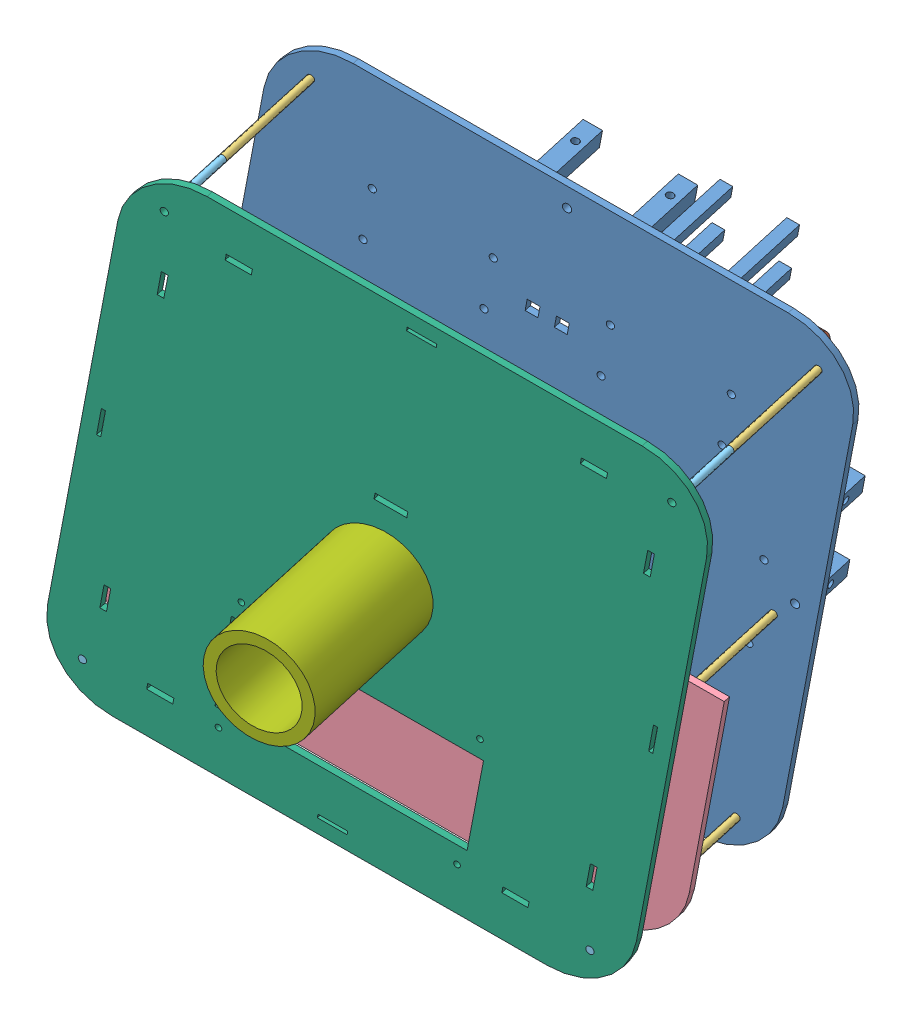
SolidWorks assembly Ensamblaje2.0, configuration Predeterminado. Lengths in mm.
Overall size (289.33 274.17 217.06).
19 component instances, 8 part files, 35 mates.
Components (placement in the parent):
- Basemenor 3.1-1: Basemenor 3.1 [Predeterminado] at (76.808 218.5631 285.9121) x (0.963383 -0.187504 -0.191664) z (0.18702 -0.042323 0.981444) size (230 230 43)
- Portamotores 3.1-1: Portamotores 3.1 [Predeterminado] at (16.9095 289.3159 299.1036) x (0.192136 0.981352 0.005706) z (0.963383 -0.187504 -0.191664) size (30 47 56.5)
- Portamotores 3.1-2: Portamotores 3.1 [Predeterminado] at (136.239 147.9161 270.2671) x (-0.192136 -0.981352 -0.005706) z (-0.963383 0.187504 0.191664) size (30 47 56.5)
- Portamotores 3.1-3: Portamotores 3.1 [Predeterminado] at (158.5268 261.7529 270.929) x (-0.192136 -0.981352 -0.005706) z (-0.963383 0.187504 0.191664) size (30 47 56.5)
- Portamotores 3.1-4: Portamotores 3.1 [Predeterminado] at (-5.3783 175.4792 298.4417) x (0.192136 0.981352 0.005706) z (0.963383 -0.187504 -0.191664) size (30 47 56.5)
- SIMULACION_Hexamonoxipuff-1: SIMULACION_Hexamonoxipuff [Predeterminado] at (191.9298 297.1399 270.4203) x (0.982348 0.003982 -0.18702) z (0.18702 -0.042323 0.981444) size (3.2 3.2 50)
- SIMULACION_Hexamonoxipuff-2: SIMULACION_Hexamonoxipuff [Predeterminado] at (153.8321 102.5533 269.2888) x (0.982348 0.003982 -0.18702) z (0.18702 -0.042323 0.981444) size (3.2 3.2 50)
- SIMULACION_Hexamonoxipuff-3: SIMULACION_Hexamonoxipuff [Predeterminado] at (0.906 334.319 308.4242) x (0.982348 0.003982 -0.18702) z (0.18702 -0.042323 0.981444) size (3.2 3.2 50)
- SIMULACION_Hexamonoxipuff-4: SIMULACION_Hexamonoxipuff [Predeterminado] at (-37.1916 139.7324 307.2927) x (0.982348 0.003982 -0.18702) z (0.18702 -0.042323 0.981444) size (3.2 3.2 50)
- SIMULACION_PCB-1: SIMULACION_PCB [Predeterminado] at (75.6722 159.8923 337.6006) x (0.963383 -0.187504 -0.191664) z (0.18702 -0.042323 0.981444) size (230 115 3)
- SIMULACION_Hexamonoxipuff-5: SIMULACION_Hexamonoxipuff [Predeterminado] at (-19.8993 228.054 307.8063) x (0.982348 0.003982 -0.18702) z (0.18702 -0.042323 0.981444) size (3.2 3.2 50)
- SIMULACION_Hexamonoxipuff-6: SIMULACION_Hexamonoxipuff [Predeterminado] at (171.1244 190.8749 269.8023) x (0.982348 0.003982 -0.18702) z (0.18702 -0.042323 0.981444) size (3.2 3.2 50)
- SIMULACION_Hexamonoxipuff_Chico-1: SIMULACION_Hexamonoxipuff_Chico [Predeterminado] at (-27.2796 137.4893 359.3092) x (0.982348 0.003982 -0.18702) z (0.18702 -0.042323 0.981444) size (3.2 3.2 30)
- SIMULACION_Hexamonoxipuff_Chico-2: SIMULACION_Hexamonoxipuff_Chico [Predeterminado] at (10.257 332.2028 357.4964) x (0.982348 0.003982 -0.18702) z (0.18702 -0.042323 0.981444) size (3.2 3.2 30)
- SIMULACION_Hexamonoxipuff_Chico-3: SIMULACION_Hexamonoxipuff_Chico [Predeterminado] at (201.2807 295.0237 319.4925) x (0.982348 0.003982 -0.18702) z (0.18702 -0.042323 0.981444) size (3.2 3.2 30)
- SIMULACION_Hexamonoxipuff_Chico-4: SIMULACION_Hexamonoxipuff_Chico [Predeterminado] at (163.7442 100.3102 321.3053) x (0.982348 0.003982 -0.18702) z (0.18702 -0.042323 0.981444) size (3.2 3.2 30)
- Basemayor-1: Basemayor [Predeterminado] at (92.3306 215.0503 367.372) x (0.963383 -0.187504 -0.191664) z (0.18702 -0.042323 0.981444) size (230 230 3)
- Cilindrokits-1: Cilindrokits [Predeterminado] at (77.3691 218.4361 288.8565) x (0.982328 0.000534 -0.187165) z (0.18702 -0.042323 0.981444) size (43.2 43.2 150)
- Portakits-1: Portakits [Predeterminado] at (50.1039 224.7974 267.8728) x (0.199566 0.978827 0.04552) z (0.973839 -0.192968 -0.120005) size (40 40 50.08)
Mates (geometry in assembly coordinates):
- Concéntrica7: concentric aligned: circle of Basemenor 3.1-1; circle of Portamotores 3.1-1
- Concéntrica8: concentric aligned: circle of Basemenor 3.1-1; circle of Portamotores 3.1-1
- Coincidente4: coincident anti-aligned: plane of Basemenor 3.1-1 through (76.808 218.5631 285.9121) normal (-0.18702 0.042323 -0.981444); plane of Portamotores 3.1-1 through (72.048 293.8581 290.0662) normal (0.18702 -0.042323 0.981444)
- Concéntrica9: concentric aligned: circle of Basemenor 3.1-1; circle of Portamotores 3.1-3
- Concéntrica10: concentric aligned: circle of Basemenor 3.1-1; circle of Portamotores 3.1-3
- Coincidente5: coincident anti-aligned: plane of Basemenor 3.1-1 through (76.808 218.5631 285.9121) normal (-0.18702 0.042323 -0.981444); plane of Portamotores 3.1-3 through (103.8558 257.1049 282.4201) normal (0.18702 -0.042323 0.981444)
- Concéntrica11: concentric aligned: circle of Basemenor 3.1-1; circle of Portamotores 3.1-2
- Concéntrica12: concentric aligned: circle of Basemenor 3.1-1; circle of Portamotores 3.1-2
- Coincidente6: coincident anti-aligned: plane of Basemenor 3.1-1 through (76.808 218.5631 285.9121) normal (-0.18702 0.042323 -0.981444); plane of Portamotores 3.1-2 through (81.568 143.2681 281.7581) normal (0.18702 -0.042323 0.981444)
- Concéntrica13: concentric aligned: circle of Basemenor 3.1-1; circle of Portamotores 3.1-4
- Concéntrica14: concentric aligned: circle of Basemenor 3.1-1; circle of Portamotores 3.1-4
- Coincidente8: coincident anti-aligned: plane of Basemenor 3.1-1 through (76.808 218.5631 285.9121) normal (-0.18702 0.042323 -0.981444); plane of Portamotores 3.1-4 through (49.7602 180.0213 289.4042) normal (0.18702 -0.042323 0.981444)
- Coincidente10: coincident aligned: circle of Basemenor 3.1-1; circle of SIMULACION_Hexamonoxipuff-1
- Coincidente11: coincident aligned: circle of Basemenor 3.1-1; circle of SIMULACION_Hexamonoxipuff-2
- Coincidente12: coincident aligned: circle of Basemenor 3.1-1; circle of SIMULACION_Hexamonoxipuff-3
- Coincidente13: coincident anti-aligned: circle of Basemenor 3.1-1; cylinder of SIMULACION_Hexamonoxipuff-4 through (-27.8406 137.6162 356.3649) axis (-0.18702 0.042323 -0.981444) radius 1.6
- Coincidente14: coincident aligned: circle of Basemenor 3.1-1; circle of SIMULACION_Hexamonoxipuff-4
- Coincidente15: coincident aligned: circle of SIMULACION_Hexamonoxipuff-4; circle of SIMULACION_PCB-1
- Coincidente17: coincident aligned: circle of SIMULACION_Hexamonoxipuff-2; circle of SIMULACION_PCB-1
- Coincidente18: coincident aligned: circle of Basemenor 3.1-1; circle of SIMULACION_Hexamonoxipuff-5
- Coincidente19: coincident anti-aligned: circle of Basemenor 3.1-1; cylinder of SIMULACION_Hexamonoxipuff-6 through (180.4754 188.7588 318.8745) axis (-0.18702 0.042323 -0.981444) radius 1.6
- Coincidente20: coincident aligned: circle of Basemenor 3.1-1; circle of SIMULACION_Hexamonoxipuff-6
- Coincidente21: coincident anti-aligned: circle of SIMULACION_PCB-1; cylinder of SIMULACION_Hexamonoxipuff_Chico-1 through (-21.669 136.2196 388.7525) axis (-0.18702 0.042323 -0.981444) radius 1.6
- Coincidente22: coincident aligned: circle of SIMULACION_PCB-1; circle of SIMULACION_Hexamonoxipuff_Chico-1
- Coincidente23: coincident aligned: circle of SIMULACION_Hexamonoxipuff-3; circle of SIMULACION_Hexamonoxipuff_Chico-2
- Coincidente24: coincident anti-aligned: circle of SIMULACION_Hexamonoxipuff-1; cylinder of SIMULACION_Hexamonoxipuff_Chico-3 through (206.8913 293.754 348.9358) axis (-0.18702 0.042323 -0.981444) radius 1.6
- Coincidente25: coincident aligned: circle of SIMULACION_Hexamonoxipuff-1; circle of SIMULACION_Hexamonoxipuff_Chico-3
- Coincidente26: coincident aligned: circle of SIMULACION_PCB-1; circle of SIMULACION_Hexamonoxipuff_Chico-4
- Coincidente27: coincident aligned: circle of SIMULACION_Hexamonoxipuff_Chico-2; circle of Basemayor-1
- Concéntrica15: concentric aligned: cylinder of SIMULACION_Hexamonoxipuff_Chico-3 through (206.8913 293.754 348.9358) axis (-0.18702 0.042323 -0.981444) radius 1.6; cylinder of Basemayor-1 through (207.4524 293.6271 351.8801) axis (-0.18702 0.042323 -0.981444) radius 1.6
- Coincidente39: coincident anti-aligned: plane of Basemenor 3.1-1 through (77.3691 218.4361 288.8565) normal (0.18702 -0.042323 0.981444); plane of Cilindrokits-1 through (77.3691 218.4361 288.8565) normal (-0.18702 0.042323 -0.981444)
- Concéntrica18: concentric anti-aligned: circle of Basemayor-1; cylinder of Cilindrokits-1 through (105.422 212.0877 436.0731) axis (-0.18702 0.042323 -0.981444) radius 21.6
- Tangente7: tangent: circle of Basemenor 3.1-1; curve of Portakits-1
- Paralelo3: parallel: plane of Basemenor 3.1-1 through (125.7771 215.5439 242.8267) normal (-0.963383 0.187504 0.191664); line of Portakits-1 through (96.2389 212.8907 244.7546) axis (0.199566 0.978827 0.04552)
- Bloquear2: lock: unknown of Cilindrokits-1; unknown of Portakits-1
